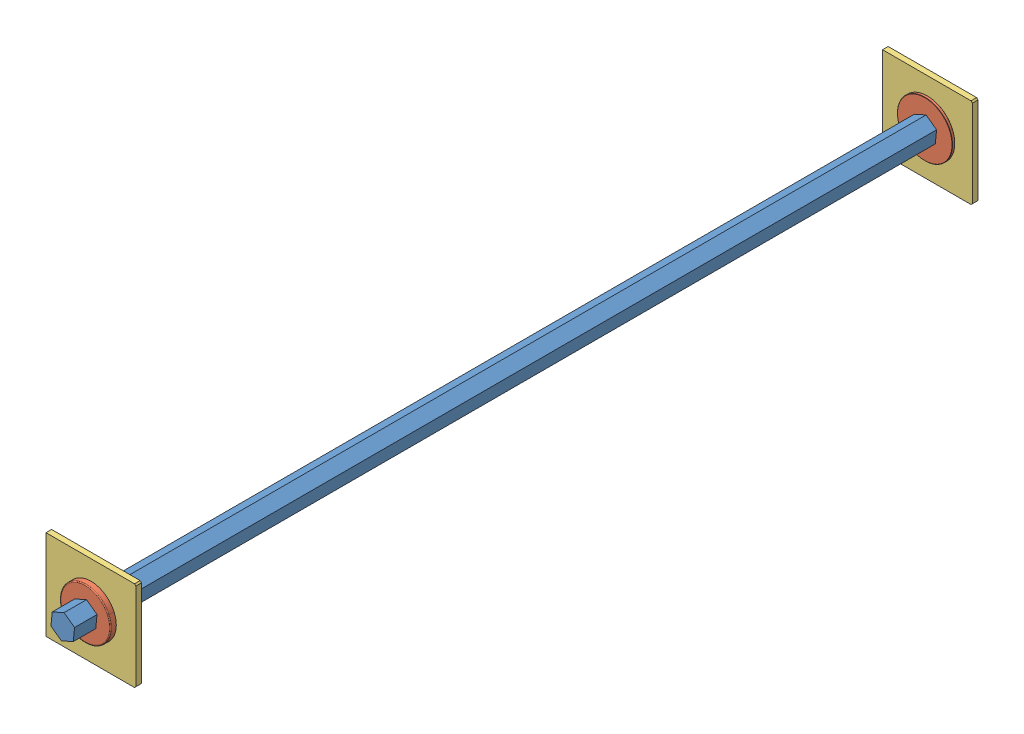
SolidWorks assembly Input, configuration Default. Lengths in mm.
Overall size (50.8 50.8 508).
5 component instances, 3 part files, 11 mates.
Components (placement in the parent):
- 20inchHexShaft-1: 20inchHexShaft [Default] at (305.0982 359.9134 265.301) x (-0.912547 -0.408971 0) z (0 0 1) size (14.66 12.7 508)
- am-2986 FR8ZZ Hex Bearing-1: am-2986 FR8ZZ Hex Bearing [Default] at (305.0982 359.9134 760.601) x (-0.912547 -0.408971 0) z (0 0 -1) size (31.12 31.12 7.93)
- am-2986 FR8ZZ Hex Bearing-2: am-2986 FR8ZZ Hex Bearing [Default] at (305.0982 359.9134 278.001) x (-0.912547 -0.408971 0) z (0 0 1) size (31.12 31.12 7.93)
- ShaftCollarHolder-1: ShaftCollarHolder [Default] at (305.0982 359.9134 284.4043) x (0 1 0) z (-1 0 0) size (50.8 3.17 50.8)
- ShaftCollarHolder-2: ShaftCollarHolder [Default] at (305.0982 359.9134 757.3727) x (0 1 0) z (-1 0 0) size (50.8 3.17 50.8)
Mates (geometry in assembly coordinates):
- Coincident10: coincident: plane of 20inchHexShaft-1 through (298.7814 360.5617 773.301) normal (-0.994775 0.102094 0); plane of am-2986 FR8ZZ Hex Bearing-1 through (299.1557 364.2087 752.6737) normal (0.994775 -0.102094 0)
- Coincident11: coincident: plane of 20inchHexShaft-1 through (308.8181 365.0597 773.301) normal (0.585804 0.810453 0); plane of am-2986 FR8ZZ Hex Bearing-1 through (311.7893 362.9121 752.6737) normal (-0.585804 -0.810453 0)
- Coincident12: coincident: plane of 20inchHexShaft-1 through (307.6952 354.1187 773.301) normal (0.408971 -0.912547 0); plane of am-2986 FR8ZZ Hex Bearing-2 through (311.0407 355.618 285.9283) normal (-0.408971 0.912547 0)
- Coincident14: coincident: plane of 20inchHexShaft-1 through (298.7814 360.5617 773.301) normal (-0.994775 0.102094 0); plane of am-2986 FR8ZZ Hex Bearing-2 through (298.4071 356.9146 285.9283) normal (0.994775 -0.102094 0)
- Concentric1: concentric: cylinder of am-2986 FR8ZZ Hex Bearing-2 through (305.0982 359.9134 285.9283) axis (0 0 -1) radius 14.2875; cylinder of ShaftCollarHolder-1 through (305.0982 359.9134 284.4043) axis (0 0 -1) radius 14.35
- Coincident15: coincident: plane of am-2986 FR8ZZ Hex Bearing-2 through (292.3499 354.2 284.4043) normal (0 0 -1); plane of ShaftCollarHolder-1 through (305.0982 359.9134 284.4043) normal (0 0 1)
- Concentric2: concentric: cylinder of am-2986 FR8ZZ Hex Bearing-1 through (305.0982 359.9134 752.6737) axis (0 0 1) radius 14.2875; cylinder of ShaftCollarHolder-2 through (305.0982 359.9134 757.3727) axis (0 0 -1) radius 14.35
- Coincident16: coincident: plane of am-2986 FR8ZZ Hex Bearing-1 through (292.3499 354.2 754.1977) normal (0 0 1); plane of ShaftCollarHolder-2 through (305.0982 359.9134 754.1977) normal (0 0 -1)
- Distance5: distance = 12.7 mm: plane of 20inchHexShaft-1 through (305.0982 359.9134 773.301) normal (0 0 1); plane of am-2986 FR8ZZ Hex Bearing-1 through (305.0982 359.9134 760.601) normal (0 0 1)
- Coincident24: coincident: plane of ShaftCollarHolder-1 through (279.6982 334.5134 281.2293) normal (-1 0 0); plane of ShaftCollarHolder-2 through (279.6982 334.5134 754.1977) normal (-1 0 0)
- Distance7: distance = 12.7 mm: plane of 20inchHexShaft-1 through (305.0982 359.9134 265.301) normal (0 0 -1); plane of am-2986 FR8ZZ Hex Bearing-2 through (305.0982 359.9134 278.001) normal (0 0 -1)
